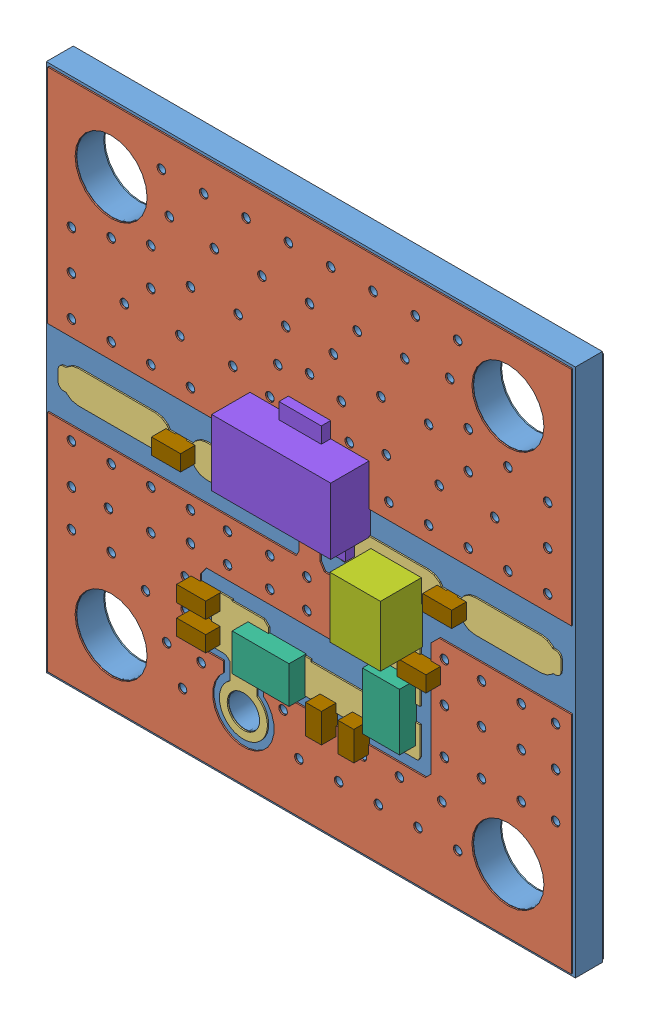
SolidWorks assembly AMPLIF89A, configuration По умолчанию. Lengths in mm.
Overall size (20 20 2.67).
19 component instances, 10 part files, 13 mates.
Components (placement in the parent):
- BoardOutline_AMPLIF89A-1: BoardOutline_AMPLIF89A [По умолчанию] at origin size (20 20 1.02)
- Copper_Layer_Top LayerAMPLIF89A-1: Copper_Layer_Top LayerAMPLIF89A [По умолчанию] at (-10 -10 1.0203) size (19.8 19.8 0.05)
  - Top Layer_AMPLIF89A_0-1: Top Layer_AMPLIF89A_0 [По умолчанию] at origin size (19.8 19.8 0.05)
  - Top Layer_AMPLIF89A_1-1: Top Layer_AMPLIF89A_1 [По умолчанию] at origin size (19.01 9.11 0.05)
- Copper_Layer_Bottom LayerAMPLIF89A-1: Copper_Layer_Bottom LayerAMPLIF89A [По умолчанию] at (-10 -10 -0.05) size (19.9 19.8 0.05)
  - Bottom Layer_AMPLIF89A_0-1: Bottom Layer_AMPLIF89A_0 [По умолчанию] at origin size (1.82 1.82 0.05)
  - Bottom Layer_AMPLIF89A_1-1: Bottom Layer_AMPLIF89A_1 [По умолчанию] at origin size (19.9 19.8 0.05)
  - Bottom Layer_AMPLIF89A_2-1: Bottom Layer_AMPLIF89A_2 [По умолчанию] at origin
- RESC2012L_R0805_1-1: RESC2012L_R0805_1 [По умолчанию] at (8.3 5.7 1.0203) x (0 1 0) z (0 0 1) size (2.15 1.4 0.65)
- RESC2012L_R0805_1-2: RESC2012L_R0805_1 [По умолчанию] at (3.75 4.825 1.0203) size (2.15 1.4 0.65)
- INDC2012X16N_L0805CS_1-1: INDC2012X16N_L0805CS_1 [По умолчанию] at (8.275 9.1 1.0203) x (0 1 0) z (0 0 1) size (2.29 1.91 1.6)
- SOT89-150P400X160-3N_SBB2089Z_1-1: SOT89-150P400X160-3N_SBB2089Z_1 [По умолчанию] at (5 11.8 1.0203) x (0 1 0) z (0 0 1) size (4 4.5 1.55)
- CAPC1005N_C0402_1-1: CAPC1005N_C0402_1 [По умолчанию] at (10.375 10 1.0203) size (1.1 0.6 0.6)
- CAPC1005N_C0402_1-2: CAPC1005N_C0402_1 [По умолчанию] at (9.4 7.4 1.0203) x (-1 0 0) z (0 0 1) size (1.1 0.6 0.6)
- CAPC1005N_C0402_1-3: CAPC1005N_C0402_1 [По умолчанию] at (5.7 3.975 1.0203) x (0 1 0) z (0 0 1) size (1.1 0.6 0.6)
- CAPC1005N_C0402_1-4: CAPC1005N_C0402_1 [По умолчанию] at (6.925 4 1.0203) x (0 1 0) z (0 0 1) size (1.1 0.6 0.6)
- CAPC1005N_C0402_1-5: CAPC1005N_C0402_1 [По умолчанию] at (0.125 10 1.0203) size (1.1 0.6 0.6)
- CAPC1005N_C0402_1-6: CAPC1005N_C0402_1 [По умолчанию] at (1.075 4.55 1.0203) size (1.1 0.6 0.6)
- CAPC1005N_C0402_1-7: CAPC1005N_C0402_1 [По умолчанию] at (1.075 5.65 1.0203) size (1.1 0.6 0.6)
Mates (geometry in assembly coordinates):
- Расстояние1: distance = 1.0203 mm aligned: plane of R2-1 through (8.3 5.7 1.0203) normal (0 0 1); plane of BoardOutline_AMPLIF89A-1 through (0 0 0) normal (0 0 1)
- Расстояние2: distance = 1.0203 mm aligned: plane of R1-2 through (3.75 4.825 1.0203) normal (0 0 1); plane of BoardOutline_AMPLIF89A-1 through (0 0 0) normal (0 0 1)
- Расстояние3: distance = 1.0203 mm aligned: plane of L1-1 through (8.275 9.1 1.0203) normal (0 0 1); plane of BoardOutline_AMPLIF89A-1 through (0 0 0) normal (0 0 1)
- Расстояние4: distance = 1.0203 mm aligned: plane of D1-1 through (5 11.8 1.0203) normal (0 0 1); plane of BoardOutline_AMPLIF89A-1 through (0 0 0) normal (0 0 1)
- Расстояние5: distance = 1.0203 mm aligned: plane of C7-1 through (10.375 10 1.0203) normal (0 0 1); plane of BoardOutline_AMPLIF89A-1 through (0 0 0) normal (0 0 1)
- Расстояние6: distance = 1.0203 mm aligned: plane of C6-2 through (9.4 7.4 1.0203) normal (0 0 1); plane of BoardOutline_AMPLIF89A-1 through (0 0 0) normal (0 0 1)
- Расстояние7: distance = 1.0203 mm aligned: plane of C5-3 through (5.7 3.975 1.0203) normal (0 0 1); plane of BoardOutline_AMPLIF89A-1 through (0 0 0) normal (0 0 1)
- Расстояние8: distance = 1.0203 mm aligned: plane of C4-4 through (6.925 4 1.0203) normal (0 0 1); plane of BoardOutline_AMPLIF89A-1 through (0 0 0) normal (0 0 1)
- Расстояние9: distance = 1.0203 mm aligned: plane of C3-5 through (0.125 10 1.0203) normal (0 0 1); plane of BoardOutline_AMPLIF89A-1 through (0 0 0) normal (0 0 1)
- Расстояние10: distance = 1.0203 mm aligned: plane of C2-6 through (1.075 4.55 1.0203) normal (0 0 1); plane of BoardOutline_AMPLIF89A-1 through (0 0 0) normal (0 0 1)
- Расстояние11: distance = 1.0203 mm aligned: plane of C1-7 through (1.075 5.65 1.0203) normal (0 0 1); plane of BoardOutline_AMPLIF89A-1 through (0 0 0) normal (0 0 1)
- Совпадение1: coincident anti-aligned: plane of BoardOutline_AMPLIF89A-1 through (0 0 1.0203) normal (0 0 1); plane of Top Layer-1/Top Layer_AMPLIF89A_0-1 through (2.5 2.5 1.0203) normal (0 0 -1)
- Совпадение3: coincident anti-aligned: plane of BoardOutline_AMPLIF89A-1 through (0 0 0) normal (0 0 -1); plane of Bottom Layer-1/Bottom Layer_AMPLIF89A_1-1 through (-10 -10 0) normal (0 0 1)
